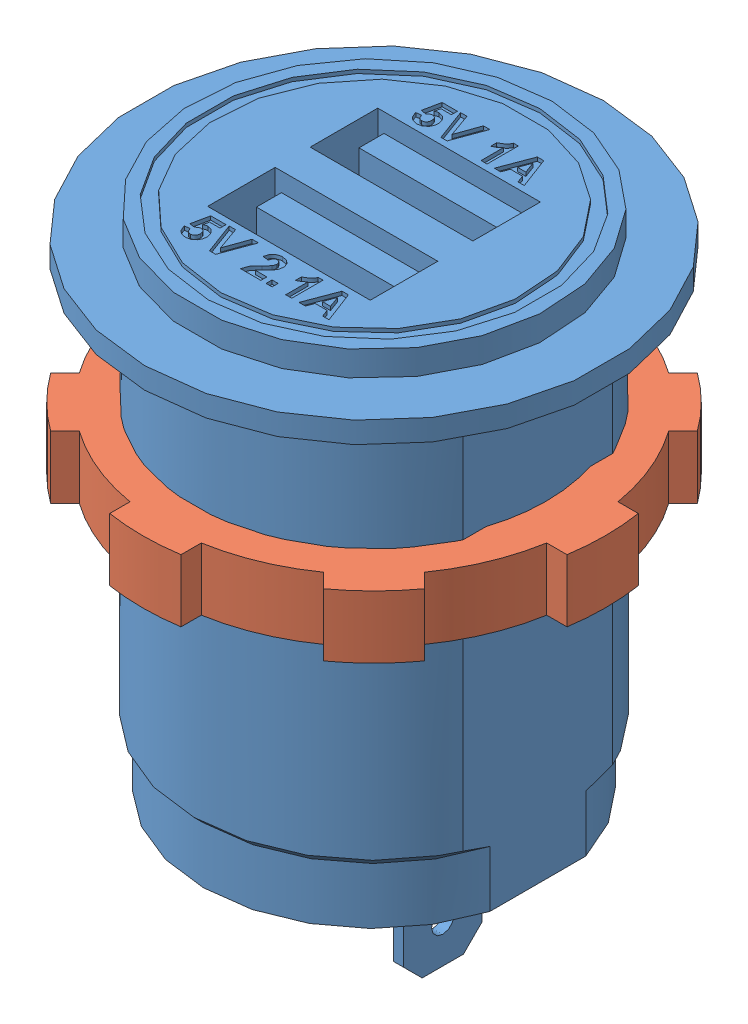
SolidWorks assembly Сборка1, configuration По умолчанию. Lengths in mm.
Overall size (37 50 37).
2 component instances, 2 part files, 2 mates.
Components (placement in the parent):
- USB car charger-1: USB car charger [По умолчанию] at origin size (36.7 50 36.7)
- Car charging nut-1: Car charging nut [По умолчанию] at (0 21.8 0) size (37 5 37)
Mates (geometry in assembly coordinates):
- Концентричный1: concentric aligned: cylinder of USB car charger-1 through (0 0 0) axis (0 -1 0) radius 14.4; cylinder of Car charging nut-1 through (0 26.8 0) axis (0 -1 0) radius 13.75
- Параллельность1: parallel aligned: plane of USB car charger-1 through (5.5 -9.5 3.15) normal (0 0 1); plane of Car charging nut-1 through (18.2792 26.8 2.85) normal (0 0 1)
